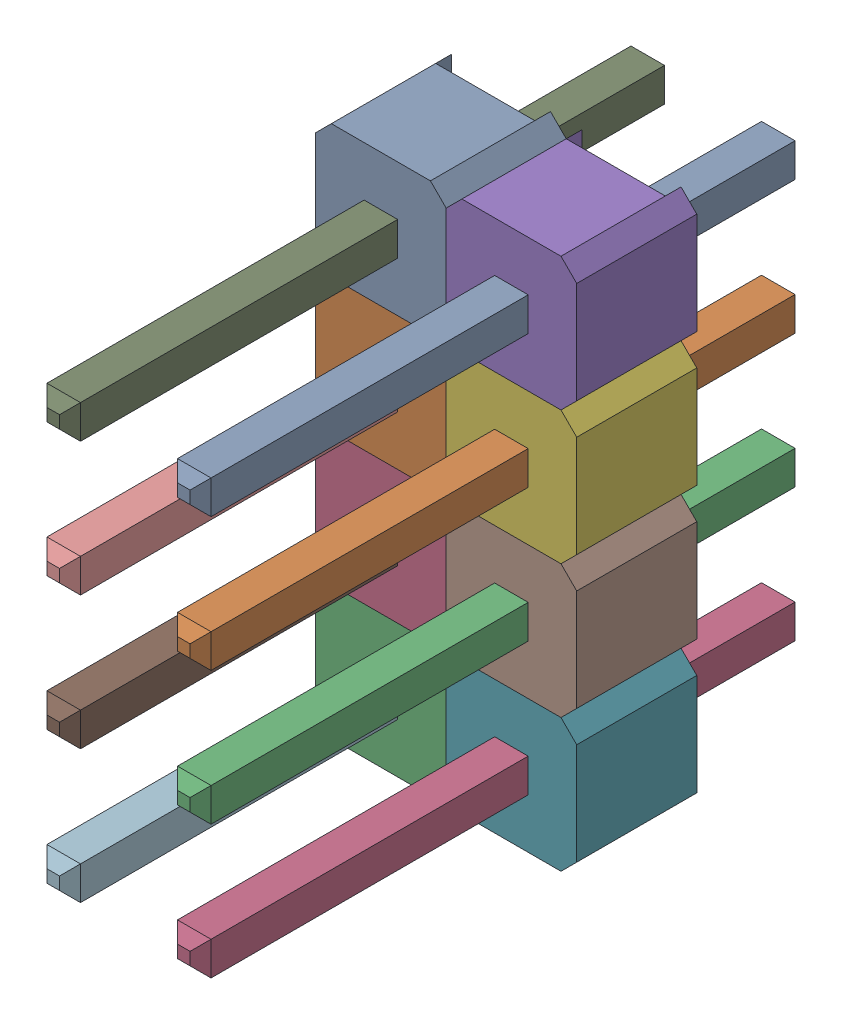
SolidWorks assembly 254-4X2, configuration ﾃﾞﾌｫﾙﾄ. Lengths in mm.
Overall size (4.98 10.16 11.54).
7 component instances, 2 part files, 0 mates.
Components (placement in the parent):
- User Library-2.54mm Male Header (4x2)-1: User Library-2.54mm Male Header (4x2) [ﾃﾞﾌｫﾙﾄ] at (-0.65 31.8 -15.24) x (0 1 0) z (0 0 1) size (10.16 4.98 11.54)
  - User Library-Header_Male_4Pin-1: User Library-Header_Male_4Pin [ﾃﾞﾌｫﾙﾄ] at (-35.6012 -1.8987 15.2958) size (10.16 2.49 11.54)
    - User Library-Header_Male_4Pin_PinArray-1: User Library-Header_Male_4Pin_PinArray [ﾃﾞﾌｫﾙﾄ] at origin size (8.26 0.64 11.54)
    - User Library-Header_Male_4Pin_BodyArray-1: User Library-Header_Male_4Pin_BodyArray [ﾃﾞﾌｫﾙﾄ] at origin size (10.16 2.49 2.29)
  - User Library-Header_Male_4Pin-1-1: User Library-Header_Male_4Pin-1 [ﾃﾞﾌｫﾙﾄ] at (-35.6012 0.5913 15.2958) size (10.16 2.49 11.54)
    - User Library-Header_Male_4Pin_PinArray-1: User Library-Header_Male_4Pin_PinArray [ﾃﾞﾌｫﾙﾄ] at origin size (8.26 0.64 11.54)
    - User Library-Header_Male_4Pin_BodyArray-1: User Library-Header_Male_4Pin_BodyArray [ﾃﾞﾌｫﾙﾄ] at origin size (10.16 2.49 2.29)
